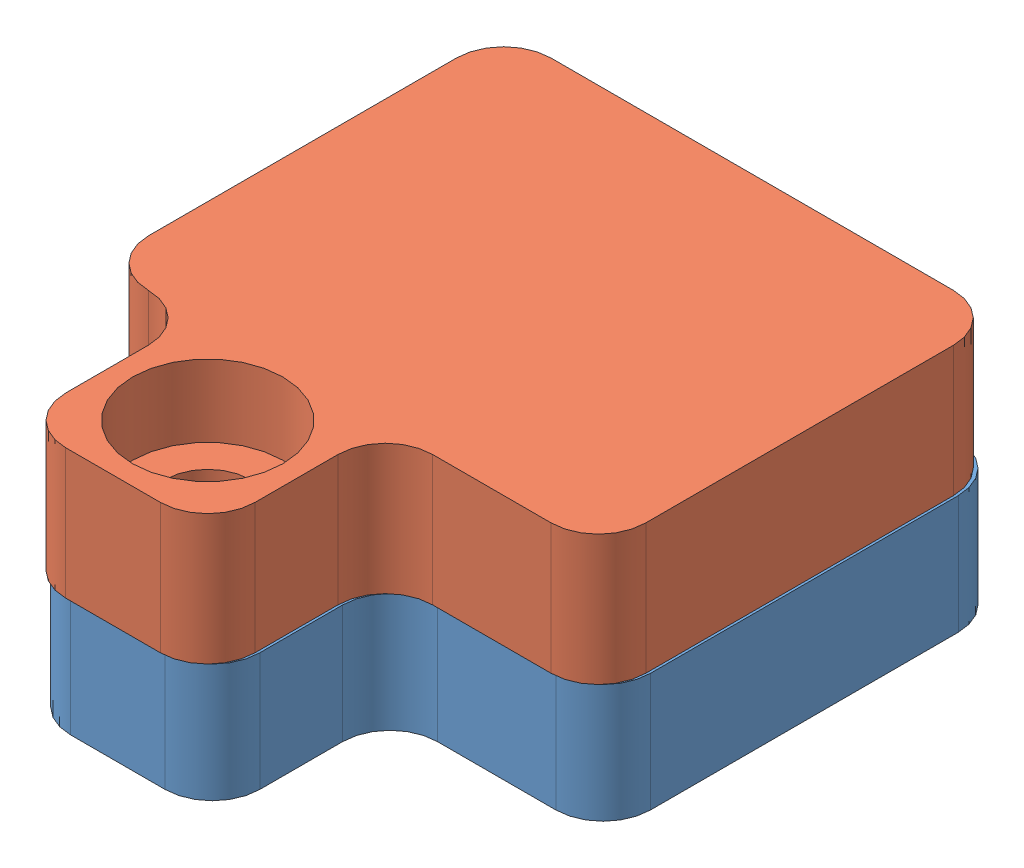
SolidWorks assembly Assem3, configuration Default. Lengths in mm.
Overall size (11.25 5.25 12.3).
2 component instances, 2 part files, 3 mates.
Components (placement in the parent):
- rectangle_window_D-1: rectangle_window_D [Default] at (-2.7086 -14.2289 8.1172) size (11.25 3.25 12.25)
- rectangle_lid_D-1: rectangle_lid_D [Default] at (-2.3836 -8.9789 8.1672) x (-1 0 0) z (0 0 1) size (10.5 4.25 12.25)
Mates (geometry in assembly coordinates):
- Coincident4: coincident anti-aligned: plane of rectangle_window_D-1 through (2.5164 -10.9789 4.2672) normal (0 0 -1); plane of rectangle_lid_D-1 through (2.5164 -10.9789 4.2672) normal (0 0 1)
- Coincident5: coincident anti-aligned: plane of rectangle_window_D-1 through (2.5164 -10.9789 11.9672) normal (1 0 0); plane of rectangle_lid_D-1 through (2.5164 -10.9789 12.0672) normal (-1 0 0)
- Coincident6: coincident anti-aligned: plane of rectangle_window_D-1 through (-8.3336 -13.2289 12.3672) normal (0 1 0); plane of rectangle_lid_D-1 through (-7.6336 -13.2289 3.9172) normal (0 -1 0)
